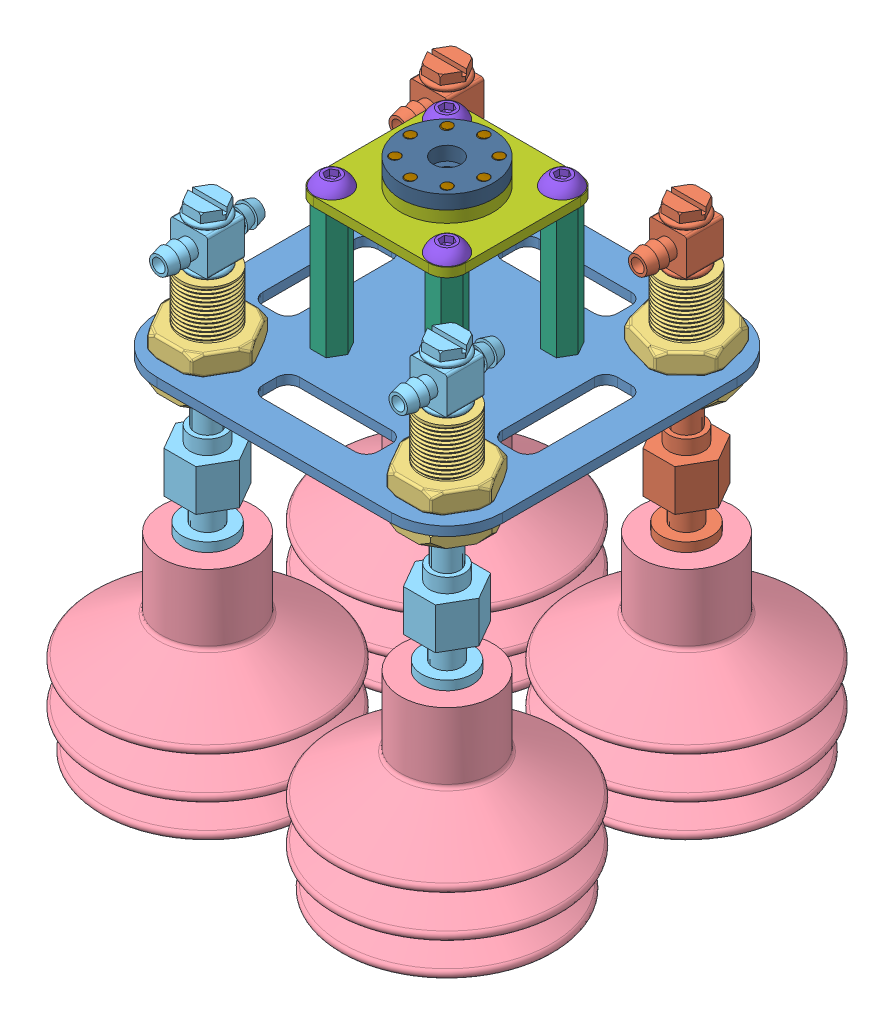
SolidWorks assembly 连杆吸盘, configuration 默认. Lengths in mm.
Overall size (103.52 112.99 102.45).
35 component instances, 10 part files, 54 mates.
Components (placement in the parent):
- 吸盘支架-1: 吸盘支架 [默认] at origin size (75 2 75)
- 继手-1: 继手 [默认] at (-26 -35.1 -26) size (49.38 104.71 49.38)
  - 继手1-1: 继手1 [默认] at origin size (13.86 62.71 16.6)
  - 继手2-2: 继手2 [默认] at (0 29.1 0) x (0.962822 0 0.270137) z (-0.270137 0 0.962822) size (19.63 21.32 17)
  - MP50吸盘-2: MP50吸盘 [默认] at (0 -15 0) size (49.38 42 49.38)
- 三通继手-1: 三通继手 [默认] at (-26 -35.1 26) size (51.52 104.71 51.52)
  - 三通继手1-1: 三通继手1 [默认] at origin size (13.86 62.71 21.2)
  - 继手2-1: 继手2 [默认] at (0 29.1 0) size (19.63 21.32 17)
  - MP50吸盘-1: MP50吸盘 [默认] at (0 -15 0) x (0.999013 0 0.044422) z (-0.044422 0 0.999013) size (49.38 42 49.38)
- 三通继手-2: 三通继手 [默认] at (26 -35.1 26) size (51.52 104.71 51.52)
  - 三通继手1-1: 三通继手1 [默认] at origin size (13.86 62.71 21.2)
  - 继手2-1: 继手2 [默认] at (0 29.1 0) size (19.63 21.32 17)
  - MP50吸盘-1: MP50吸盘 [默认] at (0 -15 0) x (0.999013 0 0.044422) z (-0.044422 0 0.999013) size (49.38 42 49.38)
- 继手-2: 继手 [默认] at (26 -35.1 -26) size (49.38 104.71 49.38)
  - 继手1-1: 继手1 [默认] at origin size (13.86 62.71 16.6)
  - 继手2-2: 继手2 [默认] at (0 29.1 0) x (0.962822 0 0.270137) z (-0.270137 0 0.962822) size (19.63 21.32 17)
  - MP50吸盘-2: MP50吸盘 [默认] at (0 -15 0) size (49.38 42 49.38)
- M4×30铜柱-1: M4×30铜柱 [默认] at (-12.5 0 -12.5) size (6.93 28 6)
- M4×30铜柱-2: M4×30铜柱 [默认] at (-12.5 0 12.5) size (6.93 28 6)
- M4×30铜柱-3: M4×30铜柱 [默认] at (12.5 0 -12.5) size (6.93 28 6)
- M4×30铜柱-4: M4×30铜柱 [默认] at (12.5 0 12.5) x (0.5 0 -0.866025) z (0.866025 0 0.5) size (6.93 28 6)
- 连接板-2: 连接板 [默认] at (0 30 0) size (33 4.5 33)
- hexagon socket button head screws gb-1: hexagon socket button head screws gb [GB_SOCKET_TYPE7 M4X16-N] at (12.5 32.2 12.5) x (0 -1 0) z (0 0 1) size (18.2 7.6 7.6)
- hexagon socket button head screws gb-2: hexagon socket button head screws gb [GB_SOCKET_TYPE7 M4X16-N] at (12.5 32.2 -12.5) x (0 -1 0) z (0 0 1) size (18.2 7.6 7.6)
- hexagon socket button head screws gb-3: hexagon socket button head screws gb [GB_SOCKET_TYPE7 M4X16-N] at (-12.5 32.2 -12.5) x (0 -1 0) z (0 0 1) size (18.2 7.6 7.6)
- hexagon socket button head screws gb-4: hexagon socket button head screws gb [GB_SOCKET_TYPE7 M4X16-N] at (-12.5 32.2 12.5) x (0 -1 0) z (0 0 1) size (18.2 7.6 7.6)
- 镙丝 PM2x8-半圆头-1: 镙丝 PM2x8-半圆头 [默认] at (8 26.8 0) x (-0.999997 0 -0.002253) z (-0.002253 0 0.999997) size (3.55 9.32 3.55)
- 镙丝 PM2x8-半圆头-2: 镙丝 PM2x8-半圆头 [默认] at (-8 26.8 0) x (-0.981299 0 0.192489) z (0.192489 0 0.981299) size (3.55 9.32 3.55)
- 镙丝 PM2x8-半圆头-3: 镙丝 PM2x8-半圆头 [默认] at (-5.6569 26.8 -5.6569) x (-0.317723 0 0.948184) z (0.948184 0 0.317723) size (3.55 9.32 3.55)
- 镙丝 PM2x8-半圆头-4: 镙丝 PM2x8-半圆头 [默认] at (-5.6569 26.8 5.6569) x (-0.996572 0 0.082729) z (0.082729 0 0.996572) size (3.55 9.32 3.55)
- 镙丝 PM2x8-半圆头-5: 镙丝 PM2x8-半圆头 [默认] at (5.6569 26.8 -5.6569) x (-0.951072 0 0.30897) z (0.30897 0 0.951072) size (3.55 9.32 3.55)
- 镙丝 PM2x8-半圆头-6: 镙丝 PM2x8-半圆头 [默认] at (0 26.8 8) x (-0.949174 0 0.314752) z (0.314752 0 0.949174) size (3.55 9.32 3.55)
- 镙丝 PM2x8-半圆头-7: 镙丝 PM2x8-半圆头 [默认] at (5.6569 26.8 5.6569) x (-0.981877 0 -0.18952) z (-0.18952 0 0.981877) size (3.55 9.32 3.55)
- 镙丝 PM2x8-半圆头-8: 镙丝 PM2x8-半圆头 [默认] at (0 26.8 -8) x (-0.861814 0 0.507224) z (0.507224 0 0.861814) size (3.55 9.32 3.55)
- 主舵盘-1: 主舵盘 [默认] at (0 35.5 0) x (-0.707107 0 -0.707107) z (-0.707107 0 0.707107) size (20 5 20)
Mates (geometry in assembly coordinates):
- 同心1: concentric anti-aligned: circle of 吸盘支架-1; circle of 继手-1/继手2-2
- 重合1: coincident anti-aligned: plane of 吸盘支架-1 through (0 0 0) normal (0 1 0); plane of 继手-1/继手2-2 through (-26 0 -26) normal (0 -1 0)
- 同心2: concentric anti-aligned: circle of 吸盘支架-1; circle of 三通继手-1/继手2-1
- 重合2: coincident anti-aligned: plane of 吸盘支架-1 through (0 0 0) normal (0 1 0); plane of 三通继手-1/继手2-1 through (-26 0 26) normal (0 -1 0)
- 平行1: parallel anti-aligned: line of 吸盘支架-1 through (-27.5 -2 12.5) axis (1 0 0); line of 三通继手-1/三通继手1-1 through (-22.5359 -18.1 20) axis (-1 0 0)
- 平行2: parallel anti-aligned: line of 吸盘支架-1 through (-24.5 -2 -12.5) axis (-1 0 0); line of 继手-1/继手1-1 through (-29.4641 -18.1 -20) axis (1 0 0)
- 同心3: concentric anti-aligned: circle of 吸盘支架-1; circle of 三通继手-2/继手2-1
- 重合5: coincident anti-aligned: plane of 吸盘支架-1 through (0 0 0) normal (0 1 0); plane of 三通继手-2/继手2-1 through (26 0 26) normal (0 -1 0)
- 平行3: parallel anti-aligned: line of 吸盘支架-1 through (24.5 -2 12.5) axis (1 0 0); line of 三通继手-2/三通继手1-1 through (29.4641 -18.1 20) axis (-1 0 0)
- 同心4: concentric aligned: circle of 吸盘支架-1; circle of 继手-2/继手1-1
- 重合7: coincident anti-aligned: plane of 吸盘支架-1 through (0 0 0) normal (0 1 0); plane of 继手-2/继手2-2 through (26 0 -26) normal (0 -1 0)
- 平行4: parallel anti-aligned: line of 吸盘支架-1 through (27.5 -2 -12.5) axis (-1 0 0); line of 继手-2/继手1-1 through (22.5359 -18.1 -20) axis (1 0 0)
- 同心5: concentric aligned: circle of 吸盘支架-1; circle of M4×30铜柱-1
- 重合9: coincident anti-aligned: plane of 吸盘支架-1 through (0 0 0) normal (0 1 0); plane of M4×30铜柱-1 through (-12.5 0 -12.5) normal (0 -1 0)
- 平行5: parallel anti-aligned: line of M4×30铜柱-1 through (-10.7679 0 -15.5) axis (-1 0 0); line of 吸盘支架-1 through (-10 0 -22) axis (1 0 0)
- 同心6: concentric aligned: circle of 吸盘支架-1; circle of M4×30铜柱-3
- 同心7: concentric aligned: circle of 吸盘支架-1; circle of M4×30铜柱-4
- 同心8: concentric aligned: circle of 吸盘支架-1; circle of M4×30铜柱-2
- 重合14: coincident anti-aligned: plane of 吸盘支架-1 through (0 0 0) normal (0 1 0); plane of M4×30铜柱-3 through (12.5 0 -12.5) normal (0 -1 0)
- 平行6: parallel anti-aligned: line of 吸盘支架-1 through (-10 0 -22) axis (1 0 0); line of M4×30铜柱-3 through (14.2321 0 -15.5) axis (-1 0 0)
- 重合16: coincident anti-aligned: plane of 吸盘支架-1 through (0 0 0) normal (0 1 0); plane of M4×30铜柱-2 through (-12.5 0 12.5) normal (0 -1 0)
- 平行8: parallel anti-aligned: line of 吸盘支架-1 through (10 0 22) axis (-1 0 0); line of M4×30铜柱-2 through (-14.2321 0 15.5) axis (1 0 0)
- 重合18: coincident anti-aligned: plane of 吸盘支架-1 through (0 0 0) normal (0 1 0); plane of M4×30铜柱-4 through (12.5 0 12.5) normal (0 -1 0)
- 平行9: parallel anti-aligned: line of 吸盘支架-1 through (10 0 22) axis (-1 0 0); line of M4×30铜柱-4 through (10.7679 0 15.5) axis (1 0 0)
- 重合20: coincident anti-aligned: plane of M4×30铜柱-1 through (-12.5 28 -12.5) normal (0 1 0); plane of 连接板-2 through (0 28 0) normal (0 -1 0)
- 同心9: concentric aligned: circle of M4×30铜柱-1; circle of 连接板-2
- 同心10: concentric aligned: circle of M4×30铜柱-3; circle of 连接板-2
- 同心13: concentric aligned: cylinder of 连接板-2 through (12.5 28 12.5) axis (0 1 0) radius 2; cylinder of hexagon socket button head screws gb-1 through (12.5 14 12.5) axis (0 1 0) radius 2
- 重合26: coincident anti-aligned: plane of 连接板-2 through (0 30 0) normal (0 1 0); plane of hexagon socket button head screws gb-1 through (12.5 30 12.5) normal (0 -1 0)
- 同心14: concentric aligned: cylinder of 连接板-2 through (12.5 28 -12.5) axis (0 1 0) radius 2; cylinder of hexagon socket button head screws gb-2 through (12.5 14 -12.5) axis (0 1 0) radius 2
- 重合27: coincident anti-aligned: plane of 连接板-2 through (0 30 0) normal (0 1 0); plane of hexagon socket button head screws gb-2 through (12.5 30 -12.5) normal (0 -1 0)
- 同心15: concentric aligned: cylinder of 连接板-2 through (-12.5 28 -12.5) axis (0 1 0) radius 2; cylinder of hexagon socket button head screws gb-3 through (-12.5 14 -12.5) axis (0 1 0) radius 2
- 重合28: coincident anti-aligned: plane of 连接板-2 through (0 30 0) normal (0 1 0); plane of hexagon socket button head screws gb-3 through (-12.5 30 -12.5) normal (0 -1 0)
- 同心16: concentric aligned: cylinder of 连接板-2 through (-12.5 28 12.5) axis (0 1 0) radius 2; cylinder of hexagon socket button head screws gb-4 through (-12.5 14 12.5) axis (0 1 0) radius 2
- 重合29: coincident anti-aligned: plane of 连接板-2 through (0 30 0) normal (0 1 0); plane of hexagon socket button head screws gb-4 through (-12.5 30 12.5) normal (0 -1 0)
- 同心17: concentric anti-aligned: circle of 连接板-2; circle of 镙丝 PM2x8-半圆头-5
- 同心18: concentric anti-aligned: circle of 连接板-2; circle of 镙丝 PM2x8-半圆头-3
- 同心19: concentric anti-aligned: circle of 连接板-2; circle of 镙丝 PM2x8-半圆头-8
- 同心20: concentric anti-aligned: circle of 连接板-2; circle of 镙丝 PM2x8-半圆头-2
- 同心21: concentric anti-aligned: circle of 连接板-2; circle of 镙丝 PM2x8-半圆头-1
- 同心22: concentric anti-aligned: circle of 连接板-2; circle of 镙丝 PM2x8-半圆头-7
- 同心23: concentric anti-aligned: circle of 连接板-2; circle of 镙丝 PM2x8-半圆头-6
- 同心24: concentric anti-aligned: circle of 连接板-2; circle of 镙丝 PM2x8-半圆头-4
- 重合30: coincident anti-aligned: plane of 连接板-2 through (0 28 0) normal (0 -1 0); plane of 镙丝 PM2x8-半圆头-1 through (8.0187 28 -8.3199) normal (0 1 0)
- 重合31: coincident anti-aligned: plane of 连接板-2 through (0 28 0) normal (0 -1 0); plane of 镙丝 PM2x8-半圆头-6 through (-2.6187 28 0.103) normal (0 1 0)
- 重合32: coincident anti-aligned: plane of 连接板-2 through (0 28 0) normal (0 -1 0); plane of 镙丝 PM2x8-半圆头-4 through (-6.3452 28 -2.6345) normal (0 1 0)
- 重合33: coincident anti-aligned: plane of 连接板-2 through (0 28 0) normal (0 -1 0); plane of 镙丝 PM2x8-半圆头-2 through (-9.6015 28 -8.1643) normal (0 1 0)
- 重合34: coincident anti-aligned: plane of 连接板-2 through (0 28 0) normal (0 -1 0); plane of 镙丝 PM2x8-半圆头-3 through (-13.5456 28 -8.3003) normal (0 1 0)
- 重合35: coincident anti-aligned: plane of 连接板-2 through (0 28 0) normal (0 -1 0); plane of 镙丝 PM2x8-半圆头-8 through (-4.22 28 -15.1702) normal (0 1 0)
- 重合36: coincident anti-aligned: plane of 连接板-2 through (0 28 0) normal (0 -1 0); plane of 镙丝 PM2x8-半圆头-7 through (7.2336 28 -2.5122) normal (0 1 0)
- 重合37: coincident anti-aligned: plane of 连接板-2 through (0 28 0) normal (0 -1 0); plane of 镙丝 PM2x8-半圆头-5 through (3.0863 28 -13.5697) normal (0 1 0)
- 重合38: coincident: plane of 连接板-2 through (0 32.5 0) normal (0 1 0); plane of 主舵盘-1 through (0 32.5 0) normal (0 -1 0)
- 同心25: concentric: circle of 连接板-2; circle of 主舵盘-1
- 同心26: concentric aligned: circle of 连接板-2; circle of 主舵盘-1
